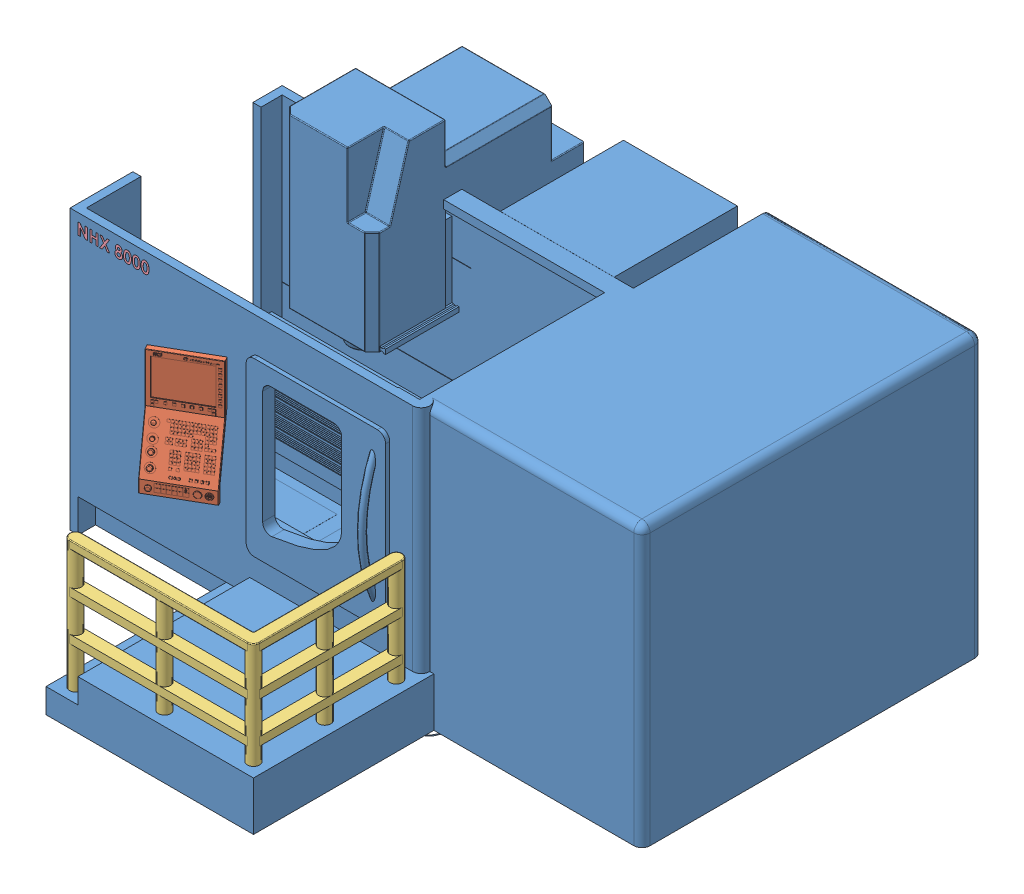
SolidWorks assembly assieme_macchina_nhx8000, configuration Default. Lengths in mm.
Overall size (6904.53 4317.04 6388.47).
4 component instances, 4 part files, 12 mates.
Components (placement in the parent):
- macchina-2: macchina [Default] at (3583.0366 1394.0706 -2115.5738) size (6904.53 4317.04 6388.47)
- tastiera-1: tastiera [Default] at (-2155.8083 -512.1833 -2772.2876) x (0.999769 0 0.021498) z (-0.021498 0 0.999769) size (761.64 1378.75 616.09)
- ringhiera-1: ringhiera [Default] at (3292.848 300 -7988.1158) x (1 0 0) z (0 1 0) size (2330.29 1899.1 1600)
- logo-1: logo [Default] at (83.8462 3180.9317 0) size (866.92 147.18 0.4)
Mates (geometry in assembly coordinates):
- Coincidente1: coincident anti-aligned: plane of macchina-1 through (-3450.38 -796.035 0) normal (0 0 1); plane of tastiera-1 through (1810.3162 2157.8161 0) normal (0 0 -1)
- Distanza2: distance = 200 mm aligned: plane of macchina-1 through (2207.7277 3001.3962 50) normal (0 1 0); plane of tastiera-1 through (2527.0442 2801.3962 -269.7203) normal (0 1 0)
- Distanza1: distance = 1400 mm: cylinder of tastiera-1 through (1338.3788 -512.1833 410.7825) axis (0 1 0) radius 5; line of macchina-1 through (3420.9317 0 0) axis (0 0 1)
- Coincidente4: coincident anti-aligned: plane of macchina-1 through (-3450.38 300 -2600) normal (0 1 0); plane of ringhiera-1 through (1998.645 300 1930.8822) normal (0 -1 0)
- Distanza3: distance = 100 mm aligned: plane of ringhiera-1 through (4178.935 1900 2005.8822) normal (0 0 1); plane of macchina-1 through (1810.9618 300 2105.8822) normal (0 0 1)
- Distanza4: distance = 100 mm aligned: plane of macchina-1 through (4353.935 300 -212.6764) normal (1 0 0); plane of ringhiera-1 through (4253.935 1900 181.7822) normal (1 0 0)
- Coincidente7: coincident anti-aligned: plane of macchina-1 through (-3450.38 -796.035 0) normal (0 0 1); plane of logo-1 through (83.8462 3180.9317 0) normal (0 0 -1)
- Distanza5: distance = 100 mm aligned: plane of logo-1 through (100 3180.9317 0.4) normal (-1 0 0); plane of macchina-1 through (0 1394.0706 -2115.5738) normal (-1 0 0)
- Distanza6: distance = 100 mm aligned: plane of logo-1 through (100 3320.9317 0.4) normal (0 1 0); plane of macchina-1 through (579.8923 3420.9317 -2600) normal (0 1 0)
- Coincidente11: coincident: plane of macchina-2 through (0 1394.0706 -2115.5738) normal (-1 0 0); plane of porta-2 through (-3294.1089 -1768.7294 -2222.9899) normal (-1 0 0)
- Coincidente12: coincident anti-aligned: plane of macchina-2 through (579.8923 3420.9317 -2600) normal (0 1 0); plane of porta-2 through (-2994.1089 1999.4125 3464.4071) normal (0 -1 0)
- Coincidente15: coincident: point of macchina-2
